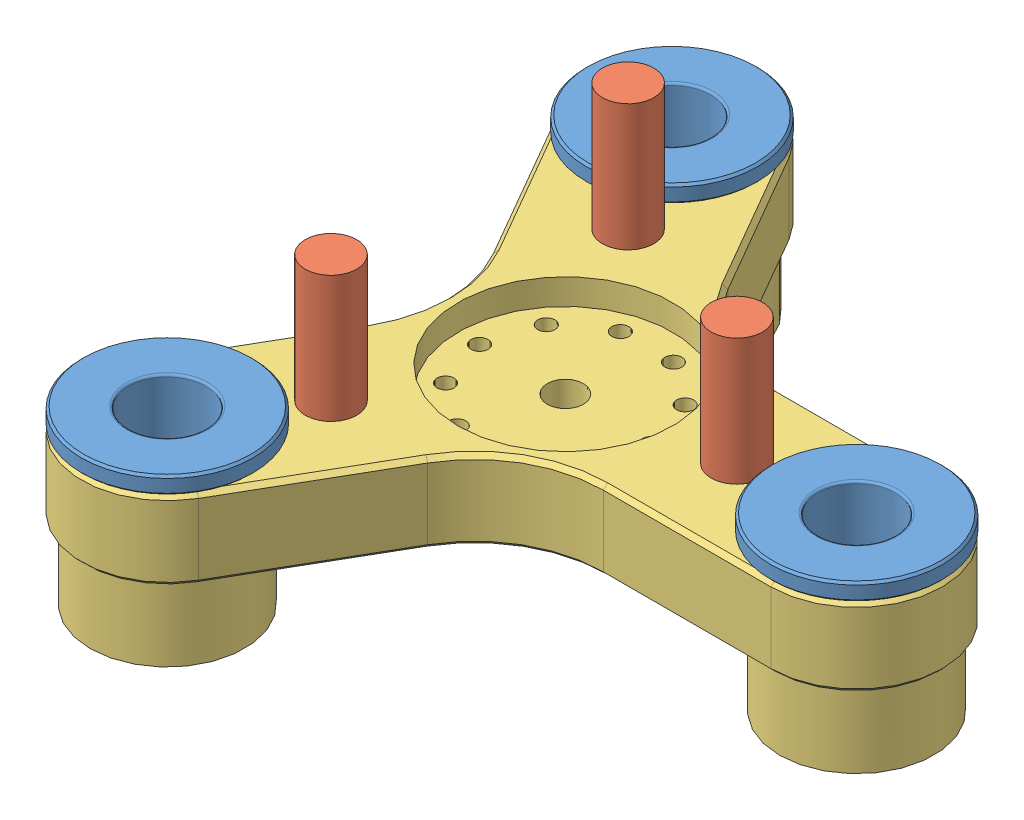
SolidWorks assembly slider_plate_top, configuration ﾃﾞﾌｫﾙﾄ. Lengths in mm.
Overall size (70.95 32.75 78.84).
7 component instances, 3 part files, 21 mates.
Components (placement in the parent):
- slider_plate_slide-1: slider_plate_slide [ﾃﾞﾌｫﾙﾄ] at (50.5087 -11.925 75.9849) size (20 20 20)
- slider_plate_slide-2: slider_plate_slide [ﾃﾞﾌｫﾙﾄ] at (-0.4452 -11.925 46.5667) size (20 20 20)
- slider_plate_slide-3: slider_plate_slide [ﾃﾞﾌｫﾙﾄ] at (-0.4452 -11.925 105.4031) size (20 20 20)
- slider_plate_stoper-2: slider_plate_stoper [ﾃﾞﾌｫﾙﾄ] at (6.5394 -21.175 58.6644) size (6 27.1 6)
- slider_plate_stoper-3: slider_plate_stoper [ﾃﾞﾌｫﾙﾄ] at (36.5394 -21.175 75.9849) size (6 27.1 6)
- slider_plate_stoper-4: slider_plate_stoper [ﾃﾞﾌｫﾙﾄ] at (6.5394 -21.175 93.3054) size (6 27.1 6)
- slider_plate_top_fixed-1: slider_plate_top_fixed [ﾃﾞﾌｫﾙﾄ] at (16.5394 -21.175 75.9849) size (70.95 18 78.84)
Mates (geometry in assembly coordinates):
- 同心円2: concentric anti-aligned: circle of ?; circle of slider_plate_slide-1
- 一致1: coincident anti-aligned: plane of ? through (-2.858 7.2753 85.0669) normal (0 1 0); plane of slider_plate_slide-1 through (27.8148 7.2753 99.018) normal (0 -1 0)
- 同心円3: concentric anti-aligned: circle of ?; circle of slider_plate_slide-3
- 一致2: coincident anti-aligned: plane of ? through (-2.858 7.2753 85.0669) normal (0 1 0); plane of slider_plate_slide-3 through (-30.2765 7.2753 104.6547) normal (0 -1 0)
- 同心円4: concentric aligned: circle of ?; circle of slider_plate_slide-2
- 一致5: coincident anti-aligned: plane of ? through (-2.858 7.2753 85.0669) normal (0 1 0); plane of slider_plate_slide-2 through (-6.1124 7.2753 51.5279) normal (0 -1 0)
- 一致6: coincident aligned: circle of ?; circle of slider_plate_stoper-2
- 一致7: coincident aligned: circle of ?; circle of slider_plate_stoper-3
- 一致8: coincident aligned: circle of ?; circle of slider_plate_stoper-4
- 同心円6: concentric: cylinder of slider_plate_slide-1 through (50.5087 -29.925 75.9849) axis (0 1 0) radius 5.75; cylinder of slider_plate_top_fixed-1 through (50.5087 -11.925 75.9849) axis (0 -1 0) radius 5.75
- 同心円7: concentric: cylinder of slider_plate_slide-3 through (-0.4452 -29.925 105.4031) axis (0 1 0) radius 5.75; cylinder of slider_plate_top_fixed-1 through (-0.4452 -11.925 105.4031) axis (0 -1 0) radius 5.75
- 同心円8: concentric: cylinder of slider_plate_slide-2 through (-0.4452 -29.925 46.5667) axis (0 1 0) radius 5.75; cylinder of slider_plate_top_fixed-1 through (-0.4452 -11.925 46.5667) axis (0 -1 0) radius 5.75
- 一致9: coincident anti-aligned: plane of slider_plate_slide-1 through (50.5087 -11.925 75.9849) normal (0 -1 0); plane of slider_plate_top_fixed-1 through (50.5087 -11.925 75.9849) normal (0 1 0)
- 一致10: coincident anti-aligned: plane of slider_plate_slide-3 through (-0.4452 -11.925 105.4031) normal (0 -1 0); plane of slider_plate_top_fixed-1 through (50.5087 -11.925 75.9849) normal (0 1 0)
- 一致11: coincident anti-aligned: plane of slider_plate_slide-2 through (-0.4452 -11.925 46.5667) normal (0 -1 0); plane of slider_plate_top_fixed-1 through (50.5087 -11.925 75.9849) normal (0 1 0)
- 同心円9: concentric: cylinder of slider_plate_stoper-3 through (36.5394 -29.6603 75.9849) axis (0 1 0) radius 3; cylinder of slider_plate_top_fixed-1 through (36.5394 -29.925 75.9849) axis (0 1 0) radius 3
- 同心円10: concentric: cylinder of slider_plate_stoper-2 through (6.5394 -29.6603 58.6644) axis (0 1 0) radius 3; cylinder of slider_plate_top_fixed-1 through (6.5394 -29.925 58.6644) axis (0 1 0) radius 3
- 同心円11: concentric: cylinder of slider_plate_stoper-4 through (6.5394 -29.6603 93.3054) axis (0 1 0) radius 3; cylinder of slider_plate_top_fixed-1 through (6.5394 -29.925 93.3054) axis (0 1 0) radius 3
- 一致12: coincident aligned: plane of slider_plate_stoper-3 through (36.5394 -21.175 75.9849) normal (0 -1 0); plane of slider_plate_top_fixed-1 through (50.5087 -21.175 75.9849) normal (0 -1 0)
- 一致13: coincident aligned: plane of slider_plate_stoper-4 through (6.5394 -21.175 93.3054) normal (0 -1 0); plane of slider_plate_top_fixed-1 through (50.5087 -21.175 75.9849) normal (0 -1 0)
- 一致14: coincident aligned: plane of slider_plate_stoper-2 through (6.5394 -21.175 58.6644) normal (0 -1 0); plane of slider_plate_top_fixed-1 through (50.5087 -21.175 75.9849) normal (0 -1 0)
